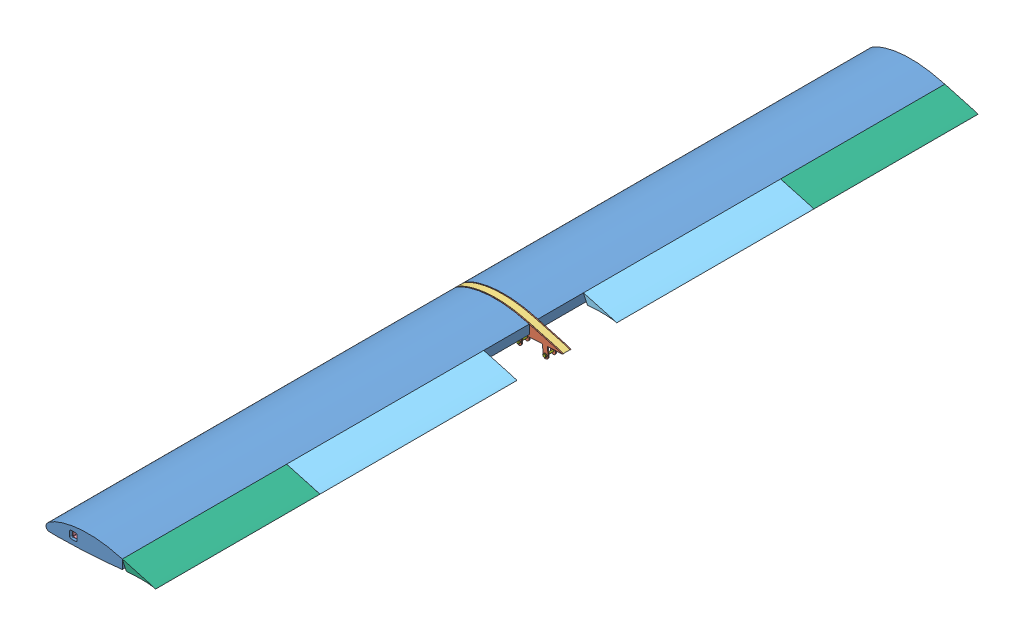
SolidWorks assembly Wing_Assembly, configuration Default. Lengths in mm.
Overall size (420.7 119.47 3147.67).
18 component instances, 8 part files, 42 mates.
Components (placement in the parent):
- Wing3.0-1: Wing3.0 [Q4s] at origin size (292.27 69.24 1557.32)
- Wing3.0-2: Wing3.0 [Q4s] at (0 0 -1590.3448) size (292.27 69.24 1557.32)
- AirfoilBracket_Wing-1: AirfoilBracket_Wing [Default] at (1.6414 -6.403 -31.115) size (419.59 119.22 3.81)
- AirfoilBracket_Wing-2: AirfoilBracket_Wing [Default] at (1.6414 -6.403 -1.905) size (419.59 119.22 3.81)
- Wing_center-1: Wing_center [Q4s] at (0 0 -29.21) size (420.7 69.24 25.4)
- WingSpar-1: WingSpar [Default] at (105.1687 18.9732 -16.51) size (27.66 27.66 3127.38)
- HLD_Flap-1: HLD_Flap [Q4s] at (-0.0496 0.4035 174.2948) x (0.999999 -0.001381 0) z (0 0 1) size (127.04 36.12 754.38)
- HLD_Flap-2: HLD_Flap [Q4s] at (-0.0496 0.4035 -961.6948) x (0.999999 -0.001381 0) z (0 0 1) size (127.04 36.12 754.38)
- Aileron-1: Aileron [Default] at (-0.0699 0.57 928.6748) x (0.999998 -0.001951 0) z (0 0 1) size (127.04 36.12 628.65)
- Aileron-2: Aileron [Default] at (-0.0699 0.57 -1590.3448) x (0.999998 -0.001951 0) z (0 0 1) size (127.04 36.12 628.65)
- hex bolt_ai-1: hex bolt_ai [HBOLT 0.2500-28x1.5x0.75-C] at (151.203 -46.0375 4.7752) x (0 0 -1) z (1 0 0) size (42.88 12.85 11.13)
- hex bolt_ai-2: hex bolt_ai [HBOLT 0.2500-28x1.5x0.75-C] at (49.7423 -51.3548 4.7752) x (0 0 -1) z (1 0 0) size (42.88 12.85 11.13)
- hex bolt_ai-3: hex bolt_ai [HBOLT 0.2500-28x1.5x0.75-C] at (252.6638 -40.7202 4.7752) x (0 0 -1) z (1 0 0) size (42.88 12.85 11.13)
- hex bolt_ai-4: hex bolt_ai [HBOLT 0.2500-28x1.5x0.75-C] at (354.1246 -35.4028 4.7752) x (0 0 -1) z (0.129381 -0.991595 0) size (42.88 12.85 11.13)
- hex nut_ai-2: hex nut_ai [HNUT 0.2500-28-D-N] at (49.7423 -51.3548 -38.7604) x (0.923728 0.383049 0) z (0 0 -1) size (11.11 12.83 5.74)
- hex nut_ai-3: hex nut_ai [HNUT 0.2500-28-D-N] at (151.203 -46.0375 -38.7604) x (0.923728 0.383049 0) z (0 0 -1) size (11.11 12.83 5.74)
- hex nut_ai-4: hex nut_ai [HNUT 0.2500-28-D-N] at (354.1246 -35.4028 -38.7604) x (0.923728 0.383049 0) z (0 0 -1) size (11.11 12.83 5.74)
- hex nut_ai-5: hex nut_ai [HNUT 0.2500-28-D-N] at (252.6638 -40.7202 -33.02) size (11.11 12.83 5.74)
Mates (geometry in assembly coordinates):
- Parallel1: parallel anti-aligned: plane of Wing3.0-1 through (0 0 0) normal (0 0 -1); plane of Wing3.0-2 through (0 0 -33.02) normal (0 0 1)
- Coincident2: coincident aligned: plane of Wing3.0-1 through (0 5.1429 1557.3248) normal (0 1 0); plane of Wing3.0-2 through (0 5.1429 -33.02) normal (0 1 0)
- Coincident3: coincident aligned: plane of Wing3.0-1 through (90.551 0 1557.3248) normal (1 0 0); plane of Wing3.0-2 through (90.551 0 -33.02) normal (1 0 0)
- Coincident4: coincident anti-aligned: plane of Wing3.0-2 through (0 0 -33.02) normal (0 0 1); plane of AirfoilBracket_Wing-1 through (304.0828 32.8759 -33.02) normal (0 0 -1)
- Coincident5: coincident aligned: plane of Wing3.0-2 through (0 5.1429 -33.02) normal (0 1 0); plane of AirfoilBracket_Wing-1 through (90.551 5.1429 -29.21) normal (0 1 0)
- Coincident6: coincident aligned: plane of Wing3.0-2 through (90.551 0 -33.02) normal (1 0 0); plane of AirfoilBracket_Wing-1 through (90.551 34.8609 -29.21) normal (1 0 0)
- Coincident8: coincident aligned: plane of Wing3.0-1 through (0 5.1429 1557.3248) normal (0 1 0); plane of AirfoilBracket_Wing-2 through (90.551 5.1429 0) normal (0 1 0)
- Coincident9: coincident aligned: plane of Wing3.0-1 through (90.551 0 1557.3248) normal (1 0 0); plane of AirfoilBracket_Wing-2 through (90.551 34.8609 0) normal (1 0 0)
- Coincident10: coincident anti-aligned: plane of Wing3.0-1 through (0 0 0) normal (0 0 -1); plane of AirfoilBracket_Wing-2 through (304.0828 32.8759 0) normal (0 0 1)
- Coincident11: coincident aligned: plane of Wing3.0-1 through (0 5.1429 1557.3248) normal (0 1 0); plane of Wing_center-1 through (0 5.1429 -3.81) normal (0 1 0)
- Coincident12: coincident aligned: plane of Wing3.0-1 through (90.551 0 1557.3248) normal (1 0 0); plane of Wing_center-1 through (90.551 0 -3.81) normal (1 0 0)
- Coincident13: coincident anti-aligned: plane of AirfoilBracket_Wing-2 through (304.0828 32.8759 -3.81) normal (0 0 -1); plane of Wing_center-1 through (0 0 -3.81) normal (0 0 1)
- Coincident14: coincident anti-aligned: plane of AirfoilBracket_Wing-1 through (304.0828 32.8759 -29.21) normal (0 0 1); plane of Wing_center-1 through (0 0 -29.21) normal (0 0 -1)
- Coincident15: coincident anti-aligned: plane of Wing3.0-1 through (118.999 0 1557.3248) normal (-1 0 0); plane of WingSpar-1 through (118.999 30.2635 1547.1775) normal (1 0 0)
- Coincident16: coincident anti-aligned: plane of Wing3.0-1 through (0 5.1429 1557.3248) normal (0 1 0); plane of WingSpar-1 through (93.8784 5.1429 1547.1775) normal (0 -1 0)
- Width1: width anti-aligned: plane of Wing3.0-2 through (0 0 -1590.3448) normal (0 0 -1); plane of Wing3.0-1 through (0 0 1557.3248) normal (0 0 1); plane of WingSpar-1 through (93.8784 7.6829 1547.1775) normal (0 0 1); plane of WingSpar-1 through (93.8784 7.6829 -1580.1975) normal (0 0 -1)
- Coincident18: coincident aligned: line of Wing3.0-1 through (292.1 36.0891 1557.3248) axis (0 0 -1); line of HLD_Flap-1 through (292.1 36.0891 928.6748) axis (0 0 -1)
- Coincident20: coincident anti-aligned: plane of HLD_Flap-1 through (-0.0496 0.4035 928.6748) normal (0 0 1); plane of Aileron-1 through (-0.0699 0.57 928.6748) normal (0 0 -1)
- Coincident21: coincident aligned: line of Wing3.0-2 through (292.1 36.0891 -33.02) axis (0 0 -1); line of HLD_Flap-2 through (292.1 36.0891 -207.3148) axis (0 0 -1)
- Coincident23: coincident aligned: line of Wing3.0-1 through (292.1 36.0891 1557.3248) axis (0 0 -1); line of Aileron-1 through (292.1 36.0891 1557.3248) axis (0 0 -1)
- Coincident24: coincident aligned: plane of Wing3.0-1 through (0 0 1557.3248) normal (0 0 1); plane of Aileron-1 through (-0.0699 0.57 1557.3248) normal (0 0 1)
- Coincident26: coincident aligned: line of Wing3.0-2 through (292.1 36.0891 -33.02) axis (0 0 -1); line of Aileron-2 through (292.1 36.0891 -961.6948) axis (0 0 -1)
- Coincident27: coincident aligned: plane of Wing3.0-2 through (0 0 -1590.3448) normal (0 0 -1); plane of Aileron-2 through (-0.0699 0.57 -1590.3448) normal (0 0 -1)
- Coincident29: coincident anti-aligned: plane of HLD_Flap-2 through (-0.0496 0.4035 -961.6948) normal (0 0 -1); plane of Aileron-2 through (-0.0699 0.57 -961.6948) normal (0 0 1)
- Parallel10: parallel aligned: plane of HLD_Flap-1 through (-0.0496 0.4035 174.2948) normal (0.001381 0.999999 0); plane of HLD_Flap-2 through (-0.0496 0.4035 -961.6948) normal (0.001381 0.999999 0)
- Parallel11: parallel aligned: plane of Aileron-1 through (-0.0699 0.57 928.6748) normal (0.001951 0.999998 0); plane of Aileron-2 through (-0.0699 0.57 -1590.3448) normal (0.001951 0.999998 0)
- Concentric1: concentric aligned: cylinder of AirfoilBracket_Wing-2 through (151.203 -46.0375 0) axis (0 0 1) radius 3.4; cylinder of hex bolt_ai-1 through (151.203 -46.0375 4.7752) axis (0 0 1) radius 3.175
- Coincident33: coincident anti-aligned: plane of AirfoilBracket_Wing-2 through (304.0828 32.8759 0) normal (0 0 1); plane of hex bolt_ai-1 through (151.203 -39.6144 0) normal (0 0 -1)
- Concentric2: concentric aligned: cylinder of AirfoilBracket_Wing-2 through (49.7423 -51.3548 0) axis (0 0 1) radius 3.4; cylinder of hex bolt_ai-2 through (49.7423 -51.3548 4.7752) axis (0 0 1) radius 3.175
- Coincident34: coincident anti-aligned: plane of AirfoilBracket_Wing-2 through (304.0828 32.8759 0) normal (0 0 1); plane of hex bolt_ai-2 through (49.7423 -44.9317 0) normal (0 0 -1)
- Concentric3: concentric aligned: cylinder of AirfoilBracket_Wing-2 through (252.6638 -40.7202 0) axis (0 0 1) radius 3.4; cylinder of hex bolt_ai-3 through (252.6638 -40.7202 4.7752) axis (0 0 1) radius 3.175
- Coincident35: coincident anti-aligned: plane of AirfoilBracket_Wing-2 through (304.0828 32.8759 0) normal (0 0 1); plane of hex bolt_ai-3 through (252.6638 -34.297 0) normal (0 0 -1)
- Concentric4: concentric aligned: cylinder of AirfoilBracket_Wing-2 through (354.1246 -35.4028 0) axis (0 0 1) radius 3.4; cylinder of hex bolt_ai-4 through (354.1246 -35.4028 4.7752) axis (0 0 1) radius 3.175
- Coincident36: coincident anti-aligned: plane of AirfoilBracket_Wing-2 through (304.0828 32.8759 0) normal (0 0 1); plane of hex bolt_ai-4 through (360.4937 -34.5718 0) normal (0 0 -1)
- Concentric5: concentric anti-aligned: cylinder of hex bolt_ai-2 through (49.7423 -51.3548 4.7752) axis (0 0 1) radius 3.175; cylinder of hex nut_ai-2 through (49.7423 -51.3548 -13.7229) axis (0 0 -1) radius 3.175
- Coincident37: coincident anti-aligned: plane of AirfoilBracket_Wing-1 through (304.0828 32.8759 -33.02) normal (0 0 -1); plane of hex nut_ai-2 through (52.1998 -57.2813 -33.02) normal (0 0 1)
- Concentric6: concentric anti-aligned: cylinder of hex bolt_ai-1 through (151.203 -46.0375 4.7752) axis (0 0 1) radius 3.175; cylinder of hex nut_ai-3 through (151.203 -46.0375 -13.7229) axis (0 0 -1) radius 3.175
- Coincident38: coincident anti-aligned: plane of AirfoilBracket_Wing-1 through (304.0828 32.8759 -33.02) normal (0 0 -1); plane of hex nut_ai-3 through (153.6606 -51.964 -33.02) normal (0 0 1)
- Concentric7: concentric anti-aligned: cylinder of hex bolt_ai-4 through (354.1246 -35.4028 4.7752) axis (0 0 1) radius 3.175; cylinder of hex nut_ai-4 through (354.1246 -35.4028 -13.7229) axis (0 0 -1) radius 3.175
- Coincident39: coincident anti-aligned: plane of AirfoilBracket_Wing-1 through (304.0828 32.8759 -33.02) normal (0 0 -1); plane of hex nut_ai-4 through (356.5821 -41.3293 -33.02) normal (0 0 1)
- Concentric8: concentric aligned: cylinder of hex bolt_ai-3 through (252.6638 -40.7202 4.7752) axis (0 0 1) radius 3.175; cylinder of hex nut_ai-5 through (252.6638 -40.7202 -38.7604) axis (0 0 1) radius 2.7051
- Coincident40: coincident anti-aligned: plane of AirfoilBracket_Wing-1 through (304.0828 32.8759 -33.02) normal (0 0 -1); plane of hex nut_ai-5 through (252.6638 -34.3044 -33.02) normal (0 0 1)
